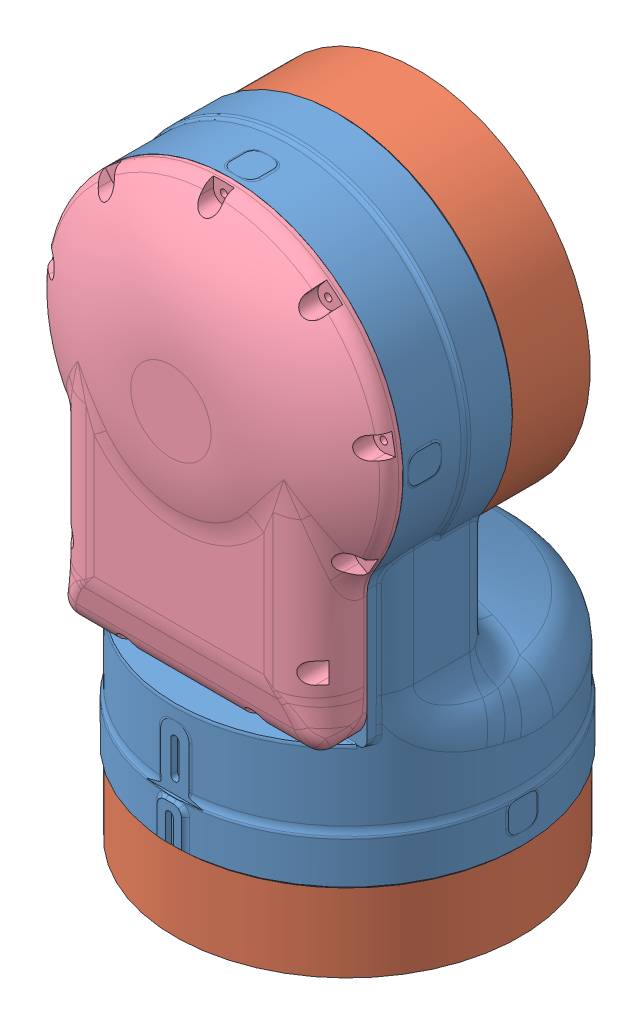
SolidWorks assembly ASM-S__ASM, configuration Valor predeterminado. Lengths in mm.
Overall size (225.13 407 221.17).
5 component instances, 4 part files, 0 mates.
Components (placement in the parent):
- S_HEAD_-1: S_HEAD_ [Valor predeterminado] at origin size (225.13 346.94 221.17)
- AC45_-1: AC45_ [Valor predeterminado] at (0 235.9 -43.5) x (-1 0 0) z (0 0 1) size (215 215 137.3)
- AC45_-2: AC45_ [Valor predeterminado] at (0 -48.5 0) x (-1 0 0) z (0 1 0) size (215 215 137.3)
- 0411564_1_-1: 0411564_1_ [Valor predeterminado] at (0 235.9 56.5) x (0 0 -1) z (1 0 0) size (111 71 71)
- S_COVER_-1: S_COVER_ [Valor predeterminado] at (0 235.9 73) x (0 1 0) z (1 0 0) size (265.88 39.63 215)
